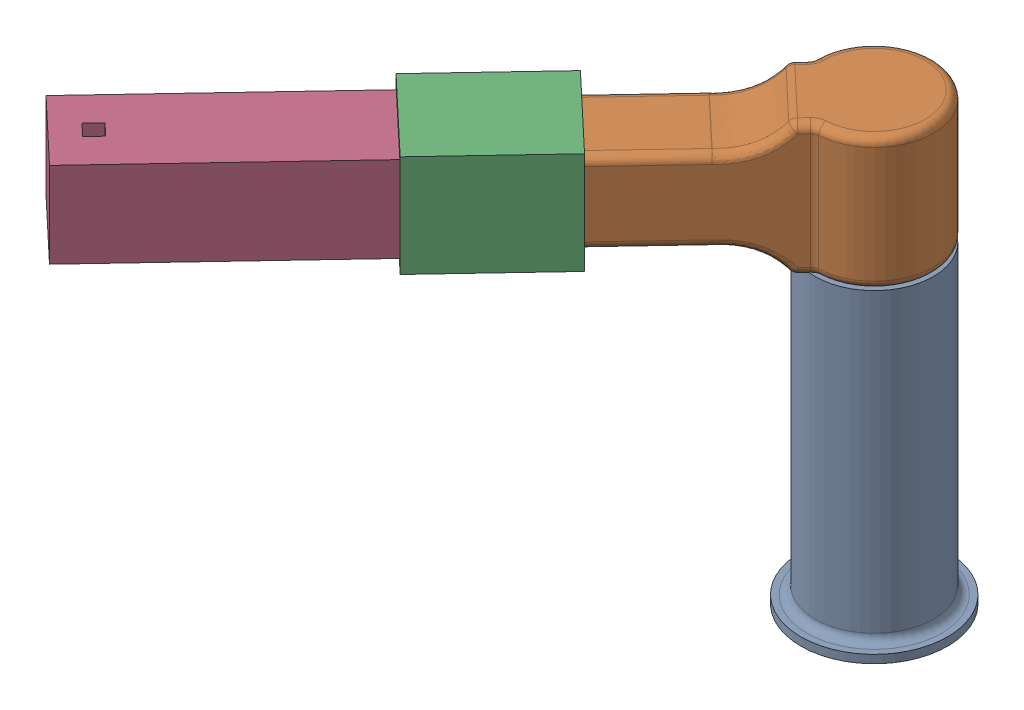
SolidWorks assembly Assem_2023, configuration Default. Lengths in mm.
Overall size (638.44 548.01 665.19).
3 component instances, 3 part files, 4 mates.
Components (placement in the parent):
- JayRPPBase-1: JayRPPBase [Default] at (685.9932 606.079 1289.2915) size (180 424 180)
- JayRPPRotation-1: JayRPPRotation [Default] at (685.9932 990.079 1289.2915) x (-0.686468 0 0.72716) z (-0.72716 0 -0.686468) size (464.5 166.03 145)
- JayRPPPrismatic1-1: JayRPPPrismatic1 [Default] at (402.3533 1071.079 1589.7445) x (-0.686468 0 0.72716) z (-0.72716 0 -0.686468) size (464 120 120)
Mates (geometry in assembly coordinates):
- Coincident1: coincident anti-aligned: plane of JayRPPBase-1 through (685.9932 1030.079 1289.2915) normal (0 1 0); circle of JayRPPRotation-1
- Concentric2: concentric aligned: cylinder of JayRPPBase-1 through (685.9932 1030.079 1289.2915) axis (0 -1 0) radius 10; cylinder of JayRPPRotation-1 through (685.9932 1030.079 1289.2915) axis (0 -1 0) radius 10
- Coincident5: coincident anti-aligned: plane of JayRPPRotation-1 through (528.5124 1081.079 1470.6745) normal (-0.72716 0 -0.686468); plane of JayRPPPrismatic1-1 through (513.9681 1081.079 1486.0809) normal (0.72716 0 0.686468)
- Coincident6: coincident anti-aligned: plane of JayRPPRotation-1 through (513.9692 1061.079 1456.9452) normal (0 1 0); plane of JayRPPPrismatic1-1 through (513.9681 1061.079 1486.0809) normal (0 -1 0)
